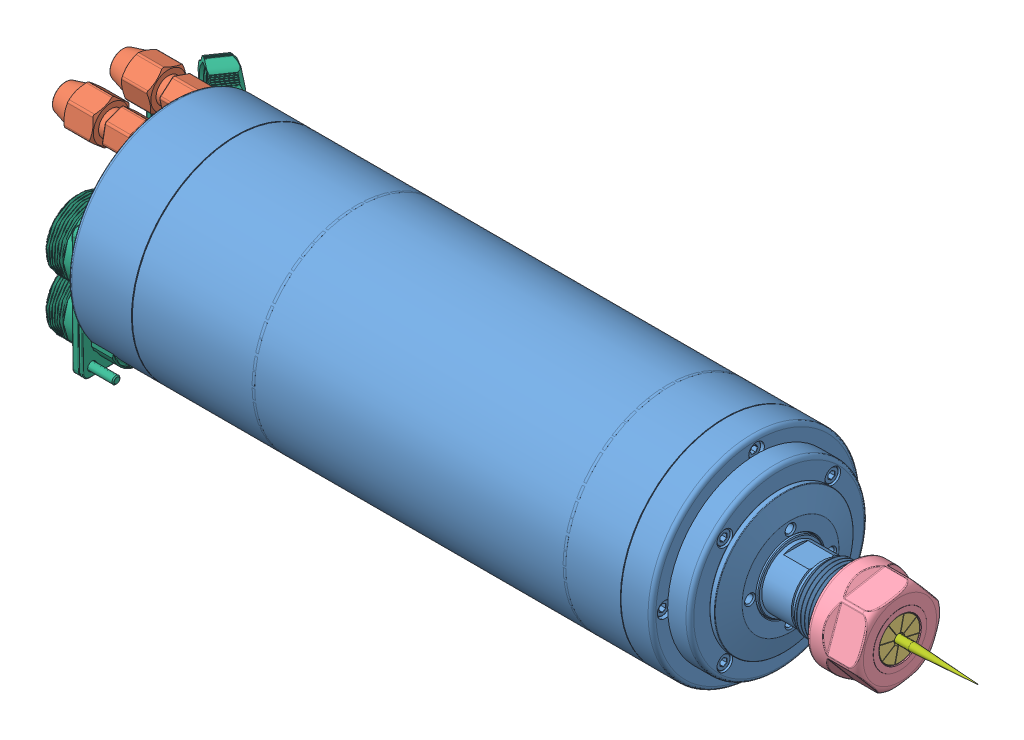
SolidWorks assembly GDZ-23, configuration По умолчанию. Lengths in mm.
Overall size (349.86 80.38 99.21).
12 component instances, 8 part files, 24 mates.
Components (placement in the parent):
- GDZ-23-1: GDZ-23 [По умолчанию] at origin size (269.23 80.02 80.02)
- Nozzle-1: Nozzle [По умолчанию] at (-267 -1.2457 0.1449) x (1 0 0) z (0 0.325645 0.945492) size (30 14 15.86)
- Nozzle-2: Nozzle [По умолчанию] at (-267 -1.1313 -0.4717) x (1 0 0) z (0 -0.335197 0.942148) size (30 14 15.86)
- Collet ER20-1: Collet ER20 [ER20] at (11.16 0 0) x (-1 0 0) z (0 0.975723 -0.219008) size (31.5 21 21)
- ER20-1: ER20 [Výchozí] at (33.4102 10.5 -50.6757) x (1 0 0) z (0 -1 0) size (30 30 19) (hidden)
- ER20-2-1: ER20-2 [Default] at (-58.6395 0 0) x (1 0 0) z (0 0.340609 0.940205) size (20.66 38.37 34)
- WS16J4Z-1: WS16J4Z [По умолчанию] at (-268.5 0 0) size (26.37 26 26)
- M3-1: M3 [По умолчанию] at (-254.5 -1.1407 20.8575) x (0 -0.999917 -0.012875) z (-1 0 0) size (30.34 74.37 55.2)
- M3-2: M3 [По умолчанию] at (-254.5 -1.1407 0.8575) x (0 -0.999917 -0.012875) z (-1 0 0) size (30.34 74.37 55.2)
- M3-3: M3 [По умолчанию] at (-254.5 -21.1407 20.8575) x (0 -0.999917 -0.012875) z (-1 0 0) size (30.34 74.37 55.2)
- M3-4: M3 [По умолчанию] at (-254.5 -21.1407 0.8575) x (0 -0.999917 -0.012875) z (-1 0 0) size (30.34 74.37 55.2)
- игла-1: игла [Default] at (-8.84 0 0) x (0 0 -1) z (1 0 0) size (3 3 50)
Mates (geometry in assembly coordinates):
- Концентричный1: concentric anti-aligned: cylinder of GDZ-23-1 through (-268.5 0 0) axis (-1 0 0) radius 11.5; cylinder of Collet ER20-1 through (11.16 0 0) axis (1 0 0) radius 8.7
- Концентричный2: concentric aligned: cylinder of GDZ-23-1 through (-268.5 0 0) axis (-1 0 0) radius 11.5; cylinder of ER20-2-1 through (-111.0294 0 0) axis (-1 0 0) radius 17
- Совпадение3: coincident: point of GDZ-23-1; point of Nozzle-1
- Совпадение4: coincident: point of GDZ-23-1; point of Nozzle-2
- Параллельность1: parallel aligned: plane of GDZ-23-1 through (-267 0 0) normal (-1 0 0); plane of Nozzle-2 through (-294.5 -1.1313 -0.4717) normal (-1 0 0)
- Параллельность2: parallel aligned: plane of GDZ-23-1 through (-267 0 0) normal (-1 0 0); plane of Nozzle-1 through (-294.5 -1.2457 0.1449) normal (-1 0 0)
- Совпадение5: coincident anti-aligned: plane of GDZ-23-1 through (-268.5 0 0) normal (-1 0 0); plane of ? through (-268.5 0 0) normal (1 0 0)
- Концентричный3: concentric anti-aligned: cylinder of GDZ-23-1 through (-268.5 0 0) axis (-1 0 0) radius 40; cylinder of ? through (-257 0 0) axis (1 0 0) radius 12
- Параллельность3: parallel aligned: plane of GDZ-23-1 through (-18.5 10.5 -40.01) normal (0 1 0); plane of ER20-1 through (33.4102 10.5 -50.6757) normal (0 1 0)
- Совпадение6: coincident aligned: plane of GDZ-23-1 through (-18.5 10.5 -40.01) normal (0 1 0); plane of ER20-1 through (33.4102 10.5 -50.6757) normal (0 1 0)
- Концентричный4: concentric aligned: cylinder of GDZ-23-1 through (0 0 0) axis (1 0 0) radius 40; cylinder of WS16J4Z-1 through (-268.5 0 0) axis (1 0 0) radius 8
- Совпадение7: coincident anti-aligned: plane of GDZ-23-1 through (-268.5 0 0) normal (-1 0 0); plane of WS16J4Z-1 through (-268.5 13 0) normal (1 0 0)
- Совпадение8: coincident aligned: plane of M3-2 through (-270 10 -10) normal (1 0 0); plane of M3-3 through (-270 -10 10) normal (1 0 0)
- Совпадение9: coincident aligned: plane of M3-2 through (-270 10 -10) normal (1 0 0); plane of M3-4 through (-270 -10 -10) normal (1 0 0)
- Совпадение10: coincident aligned: plane of M3-1 through (-270 10 10) normal (1 0 0); plane of M3-2 through (-270 10 -10) normal (1 0 0)
- Концентричный6: concentric aligned: cylinder of WS16J4Z-1 through (-265.9597 10 10) axis (-1 0 0) radius 1.75; cylinder of M3-1 through (-256.5 10 10) axis (-1 0 0) radius 1.5
- Концентричный7: concentric aligned: cylinder of WS16J4Z-1 through (-265.9597 10 -10) axis (-1 0 0) radius 1.75; cylinder of M3-2 through (-256.5 10 -10) axis (-1 0 0) radius 1.5
- Концентричный8: concentric aligned: cylinder of WS16J4Z-1 through (-265.9597 -10 10) axis (-1 0 0) radius 1.75; cylinder of M3-3 through (-256.5 -10 10) axis (-1 0 0) radius 1.5
- Концентричный9: concentric aligned: cylinder of WS16J4Z-1 through (-265.9597 -10 -10) axis (-1 0 0) radius 1.75; cylinder of M3-4 through (-256.5 -10 -10) axis (-1 0 0) radius 1.5
- Совпадение11: coincident anti-aligned: plane of WS16J4Z-1 through (-270 9 0) normal (-1 0 0); plane of M3-3 through (-270 -10 10) normal (1 0 0)
- Coincident1: coincident aligned: cone of Collet ER20-1 through (11.16 0 0) axis (1 0 0); cone of ER20-2-1 through (10.7767 0 0) axis (1 0 0)
- Coincident2: coincident aligned: cone of GDZ-23-1 through (-23.125 0 0) axis (-1 0 0); cone of Collet ER20-1 through (3.5577 0 0) axis (-1 0 0)
- Concentric1: concentric anti-aligned: cylinder of Collet ER20-1 through (11.16 0 0) axis (1 0 0) radius 1.5; cylinder of игла-1 through (49.1654 0 0) axis (-1 0 0) radius 1.5
- Distance1: distance = 30 mm aligned: plane of игла-1 through (41.16 0 0) normal (1 0 0); plane of Collet ER20-1 through (11.16 0 0) normal (1 0 0)
